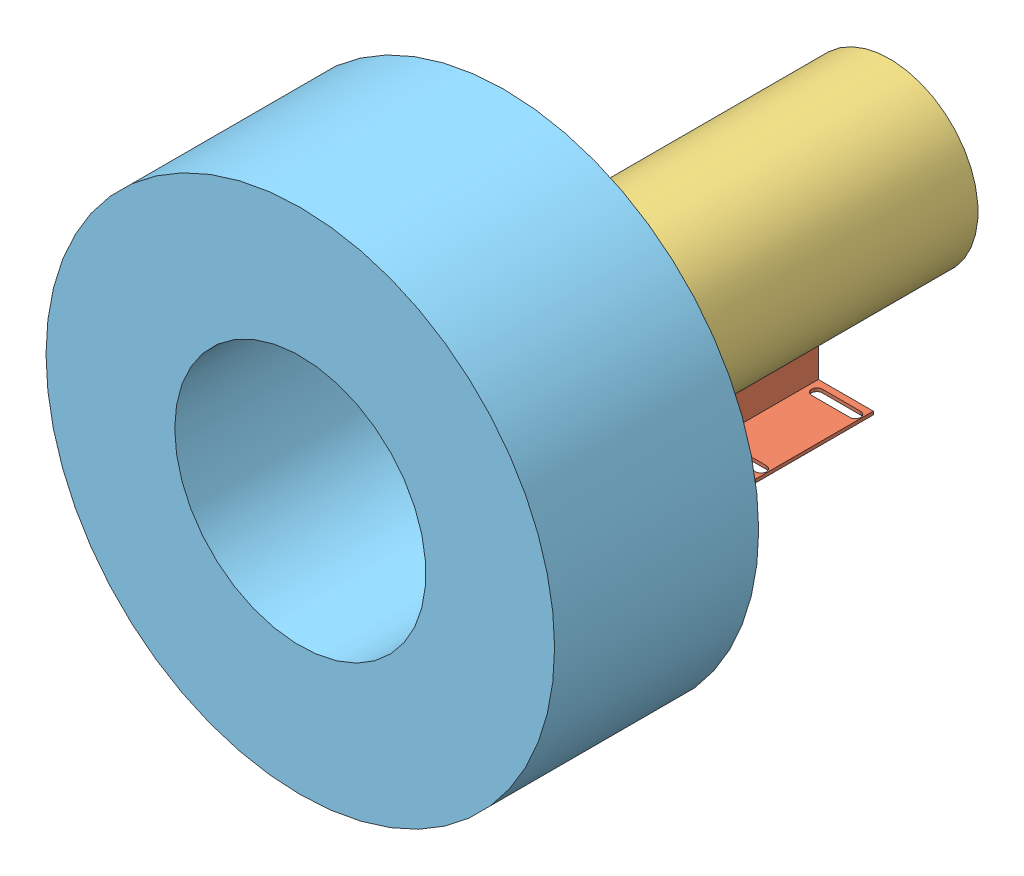
SolidWorks assembly Wheel_Motor_Ass, configuration Default. Lengths in mm.
Overall size (411.48 411.48 476.76).
17 component instances, 7 part files, 34 mates.
Components (placement in the parent):
- Wheel Hub-1: Wheel Hub [Default] at (14.289 67.5101 114.1198) size (127 127 48.26)
- MotorAss-1: MotorAss [Default] at (14.289 -20.0691 -89.0802) size (165.1 171.45 298.96)
  - motorMount-1: motorMount [Default] at origin size (165.1 28.4 95.25)
  - motor-1: motor [Default] at (0 87.5792 -95.758) size (165.1 165.1 298.96)
- hex bolt_ai-1: hex bolt_ai [HBOLT 0.4375-20x1.375x1.125-N] at (-36.511 67.5101 106.0934) x (0 0 1) z (-0.866025 -0.5 0) size (42.95 18.33 15.88)
- hex bolt_ai-2: hex bolt_ai [HBOLT 0.4375-20x1.375x1.125-N] at (14.289 118.3101 106.0934) x (0 0 1) z (0 -1 0) size (42.95 18.33 15.88)
- hex bolt_ai-3: hex bolt_ai [HBOLT 0.4375-20x1.375x1.125-N] at (14.289 16.7101 106.0934) x (0 0 1) z (-0.866025 0.5 0) size (42.95 18.33 15.88)
- hex bolt_ai-4: hex bolt_ai [HBOLT 0.4375-20x1.375x1.125-N] at (65.089 67.5101 106.0934) x (0 0 1) z (-0.866025 0.5 0) size (42.95 18.33 15.88)
- Tire-1: Tire [Default] at (14.289 67.5101 129.9948) x (-1 0 0) z (0 0 -1) size (411.48 411.48 165.1)
- flat washer type a wide_ai-1: flat washer type a wide_ai [Preferred Wide FW 0.4375] at (-36.511 67.5101 132.103) x (0 0 1) z (-0.923728 -0.383049 0) size (2.11 31.75 31.75)
- flat washer type a wide_ai-2: flat washer type a wide_ai [Preferred Wide FW 0.4375] at (14.289 118.3101 132.103) x (0 0 1) z (1 0 0) size (2.11 31.75 31.75)
- flat washer type a wide_ai-3: flat washer type a wide_ai [Preferred Wide FW 0.4375] at (14.289 16.7101 132.103) x (0 0 1) z (1 0 0) size (2.11 31.75 31.75)
- flat washer type a wide_ai-4: flat washer type a wide_ai [Preferred Wide FW 0.4375] at (65.089 67.5101 132.103) x (0 0 1) z (1 0 0) size (2.11 31.75 31.75)
- hex thick nut_ai-1: hex thick nut_ai [HTNUT 0.4375-14-D-N] at (14.289 16.7101 143.8632) x (0.055202 -0.998475 0) z (0 0 1) size (17.48 20.18 11.76)
- hex thick nut_ai-2: hex thick nut_ai [HTNUT 0.4375-14-D-N] at (-36.511 67.5101 143.8632) x (0.547044 -0.837104 0) z (0 0 1) size (17.48 20.18 11.76)
- hex thick nut_ai-3: hex thick nut_ai [HTNUT 0.4375-14-D-N] at (65.089 67.5101 143.8632) x (-0.982324 -0.18719 0) z (0 0 1) size (17.48 20.18 11.76)
- hex thick nut_ai-4: hex thick nut_ai [HTNUT 0.4375-14-D-N] at (14.289 118.3101 143.8632) x (0.055202 -0.998475 0) z (0 0 1) size (17.48 20.18 11.76)
Mates (geometry in assembly coordinates):
- Concentric2: concentric: cylinder of Wheel Hub-1 through (14.289 67.5101 78.5598) axis (0 0 1) radius 7.9375; cylinder of MotorAss-1/motor-1 through (14.289 67.5101 114.1198) axis (0 0 -1) radius 7.9375
- Parallel4: parallel: line of Wheel Hub-1 through (11.876 70.6216 78.5598) axis (1 0 0); line of MotorAss-1/motor-1 through (11.876 73.0346 114.1198) axis (1 0 0)
- Coincident5: coincident: plane of Wheel Hub-1 through (14.289 67.5101 114.1198) normal (0 0 -1); plane of MotorAss-1/motor-1 through (14.289 67.5101 114.1198) normal (0 0 1)
- Concentric3: concentric: cylinder of Wheel Hub-1 through (-36.511 67.5101 126.8198) axis (0 0 -1) radius 5.5563; cylinder of hex bolt_ai-1 through (-36.511 67.5101 106.0934) axis (0 0 -1) radius 5.5563
- Coincident6: coincident: plane of Wheel Hub-1 through (14.289 67.5101 114.1198) normal (0 0 -1); plane of hex bolt_ai-1 through (-41.0937 75.4476 114.1198) normal (0 0 1)
- Parallel5: parallel: line of MotorAss-1/motorMount-1 through (-68.261 -21.3899 6.1698) axis (1 0 0); line of hex bolt_ai-1 through (-41.0937 59.5726 114.1198) axis (1 0 0)
- Concentric4: concentric: cylinder of Wheel Hub-1 through (14.289 118.3101 126.8198) axis (0 0 -1) radius 5.5563; cylinder of hex bolt_ai-2 through (14.289 118.3101 106.0934) axis (0 0 -1) radius 5.5563
- Concentric5: concentric: cylinder of Wheel Hub-1 through (65.089 67.5101 126.8198) axis (0 0 -1) radius 5.5563; cylinder of hex bolt_ai-4 through (65.089 67.5101 106.0934) axis (0 0 -1) radius 5.5563
- Concentric6: concentric: cylinder of Wheel Hub-1 through (14.289 16.7101 126.8198) axis (0 0 -1) radius 5.5563; cylinder of hex bolt_ai-3 through (14.289 16.7101 106.0934) axis (0 0 -1) radius 5.5563
- Coincident8: coincident: plane of Wheel Hub-1 through (14.289 67.5101 114.1198) normal (0 0 -1); plane of hex bolt_ai-4 through (69.6718 75.4476 114.1198) normal (0 0 1)
- Parallel6: parallel: line of MotorAss-1/motorMount-1 through (-68.261 -21.3899 6.1698) axis (1 0 0); line of hex bolt_ai-4 through (60.5063 59.5726 114.1198) axis (1 0 0)
- Coincident10: coincident: plane of Wheel Hub-1 through (14.289 67.5101 114.1198) normal (0 0 -1); plane of hex bolt_ai-3 through (18.8718 24.6476 114.1198) normal (0 0 1)
- Parallel7: parallel: line of MotorAss-1/motorMount-1 through (-68.261 -21.3899 6.1698) axis (1 0 0); line of hex bolt_ai-3 through (9.7063 8.7726 114.1198) axis (1 0 0)
- Coincident12: coincident: plane of Wheel Hub-1 through (14.289 67.5101 114.1198) normal (0 0 -1); plane of hex bolt_ai-2 through (5.1236 118.3101 114.1198) normal (0 0 1)
- Parallel8: parallel: line of MotorAss-1/motorMount-1 through (-68.261 -21.3899 6.1698) axis (1 0 0); line of hex bolt_ai-2 through (9.7063 110.3726 114.1198) axis (1 0 0)
- Concentric7: concentric: cylinder of Tire-1 through (14.289 16.7101 126.8198) axis (0 0 1) radius 5.5563; cylinder of hex bolt_ai-3 through (14.289 16.7101 106.0934) axis (0 0 -1) radius 5.5563
- Concentric10: concentric: cylinder of hex bolt_ai-1 through (-36.511 67.5101 106.0934) axis (0 0 -1) radius 5.5563; cylinder of Tire-1 through (-36.511 67.5101 126.8198) axis (0 0 1) radius 5.5563
- Coincident14: coincident: plane of Wheel Hub-1 through (14.289 67.5101 126.8198) normal (0 0 1); plane of Tire-1 through (14.289 67.5101 126.8198) normal (0 0 -1)
- Concentric11: concentric: cylinder of hex bolt_ai-4 through (65.089 67.5101 106.0934) axis (0 0 -1) radius 5.5563; cylinder of flat washer type a wide_ai-4 through (65.089 67.5101 97.178) axis (0 0 -1) radius 6.35
- Concentric12: concentric: cylinder of hex bolt_ai-2 through (14.289 118.3101 106.0934) axis (0 0 -1) radius 5.5563; cylinder of flat washer type a wide_ai-2 through (14.289 118.3101 97.178) axis (0 0 -1) radius 6.35
- Concentric13: concentric: cylinder of hex bolt_ai-3 through (14.289 16.7101 106.0934) axis (0 0 -1) radius 5.5563; cylinder of flat washer type a wide_ai-3 through (14.289 16.7101 97.178) axis (0 0 -1) radius 6.35
- Concentric14: concentric: circle of hex bolt_ai-1; cylinder of flat washer type a wide_ai-1 through (-36.511 67.5101 97.178) axis (0 0 -1) radius 6.35
- Coincident15: coincident: plane of Tire-1 through (14.289 67.5101 129.9948) normal (0 0 1); plane of flat washer type a wide_ai-2 through (14.289 102.4351 129.9948) normal (0 0 -1)
- Coincident17: coincident: plane of Tire-1 through (14.289 67.5101 129.9948) normal (0 0 1); plane of flat washer type a wide_ai-1 through (-42.5919 82.1743 129.9948) normal (0 0 -1)
- Coincident18: coincident: plane of Tire-1 through (14.289 67.5101 129.9948) normal (0 0 1); plane of flat washer type a wide_ai-4 through (65.089 51.6351 129.9948) normal (0 0 -1)
- Coincident19: coincident: plane of Tire-1 through (14.289 67.5101 129.9948) normal (0 0 1); plane of flat washer type a wide_ai-3 through (14.289 0.8351 129.9948) normal (0 0 -1)
- Concentric15: concentric: cylinder of hex bolt_ai-1 through (-36.511 67.5101 106.0934) axis (0 0 -1) radius 5.5563; cylinder of hex thick nut_ai-2 through (-36.511 67.5101 880.3124) axis (0 0 1) radius 4.6736
- Concentric16: concentric: cylinder of hex bolt_ai-3 through (14.289 16.7101 106.0934) axis (0 0 -1) radius 5.5563; cylinder of hex thick nut_ai-1 through (14.289 16.7101 132.103) axis (0 0 1) radius 4.6736
- Concentric17: concentric: cylinder of hex bolt_ai-2 through (14.289 118.3101 106.0934) axis (0 0 -1) radius 5.5563; circle of hex thick nut_ai-4
- Concentric18: concentric: cylinder of hex thick nut_ai-3 through (65.089 67.5101 669.9567) axis (0 0 1) radius 4.6736; circle of hex bolt_ai-4
- Coincident21: coincident: plane of flat washer type a wide_ai-3 through (14.289 10.3601 132.103) normal (0 0 1); plane of hex thick nut_ai-1 through (24.363 17.267 132.103) normal (0 0 -1)
- Coincident22: coincident: plane of flat washer type a wide_ai-1 through (-38.9433 73.3758 132.103) normal (0 0 1); plane of hex thick nut_ai-2 through (-28.0652 73.0294 132.103) normal (0 0 -1)
- Coincident23: coincident: plane of flat washer type a wide_ai-4 through (65.089 61.1601 132.103) normal (0 0 1); plane of hex thick nut_ai-3 through (66.9777 57.5991 132.103) normal (0 0 -1)
- Coincident24: coincident: plane of flat washer type a wide_ai-2 through (14.289 111.9601 132.103) normal (0 0 1); plane of hex thick nut_ai-4 through (24.363 118.867 132.103) normal (0 0 -1)
